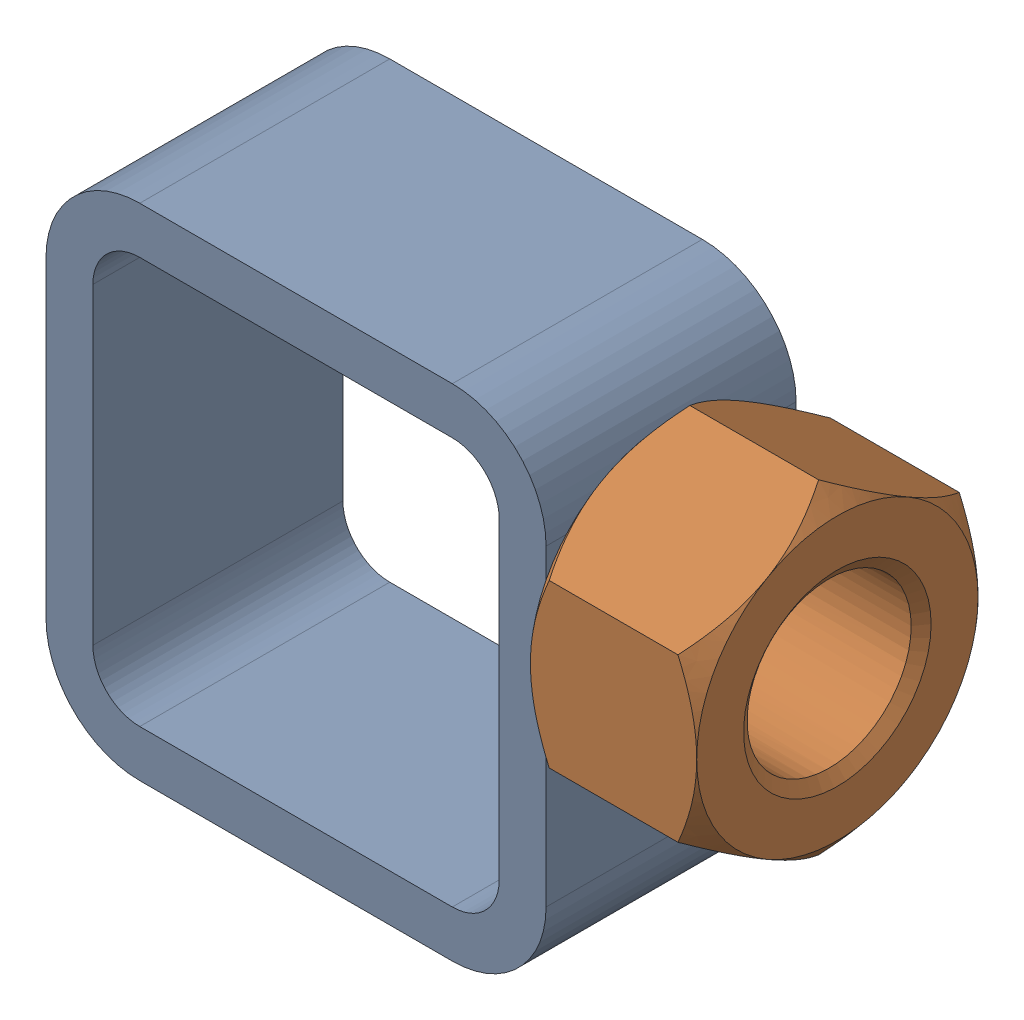
SolidWorks assembly 01-005-00-0-3, configuration Default. Lengths in mm.
Overall size (67.69 50.8 28.57).
2 component instances, 2 part files, 0 mates.
Components (placement in the parent):
- tube square_ai(PreviewCfg)-1: tube square_ai(PreviewCfg) [Default] at origin size (50.8 50.8 25.4)
- hex nut_ai(HNUT 0.7500-10-D-C)-1: hex nut_ai(HNUT 0.7500-10-D-C) [Default] at (67.691 31.75 0) x (0 0 -1) z (1 0 0) size (28.57 33 16.89)
